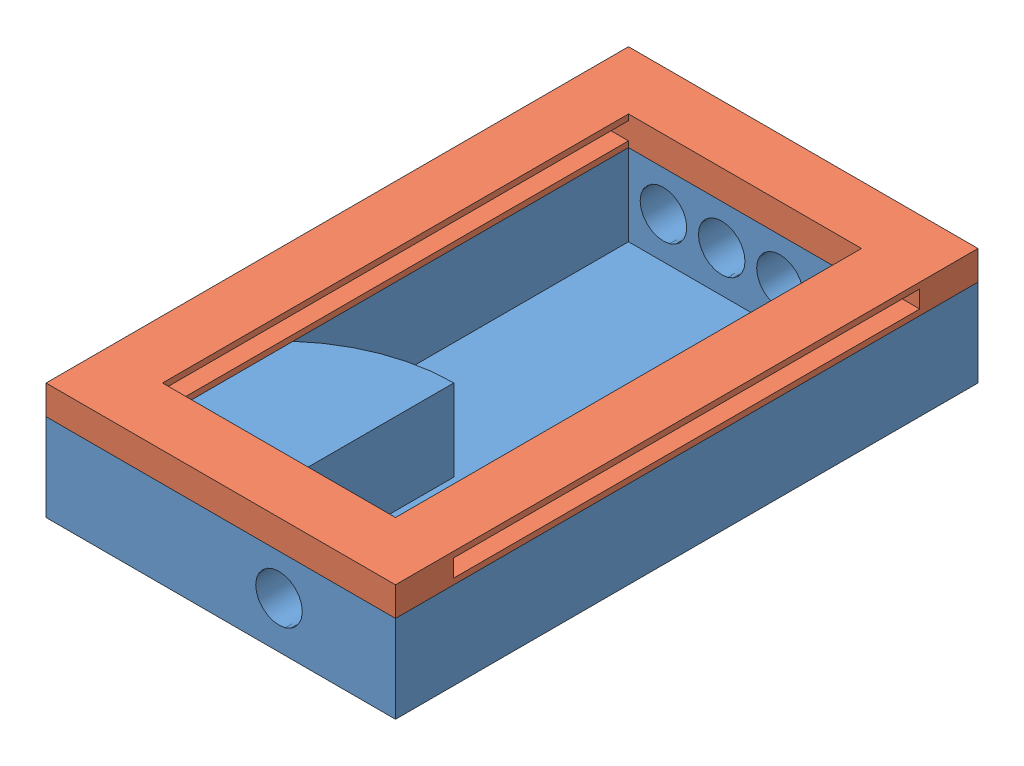
SolidWorks assembly Ensamblaje1, configuration Predeterminado. Lengths in mm.
Overall size (60 20 100).
2 component instances, 2 part files, 3 mates.
Components (placement in the parent):
- Pieza_1-1: Pieza_1 [Predeterminado] at (64.0676 15.5512 50) size (60 15 100)
- Pieza_2_tapa-1: Pieza_2_tapa [Predeterminado] at (64.0676 35.5512 -50) x (1 0 0) z (0 -1 0) size (60 100 5)
Mates (geometry in assembly coordinates):
- Coincidente1: coincident: plane of Pieza_1-1 through (64.0676 30.5512 50) normal (0 1 0); plane of Pieza_2_tapa-1 through (64.0676 30.5512 -50) normal (0 -1 0)
- Coincidente2: coincident: plane of Pieza_1-1 through (64.0676 30.5512 50) normal (1 0 0); plane of Pieza_2_tapa-1 through (64.0676 30.5512 -50) normal (1 0 0)
- Coincidente3: coincident aligned: plane of Pieza_1-1 through (64.0676 30.5512 -50) normal (0 0 -1); plane of Pieza_2_tapa-1 through (64.0676 30.5512 -50) normal (0 0 -1)
